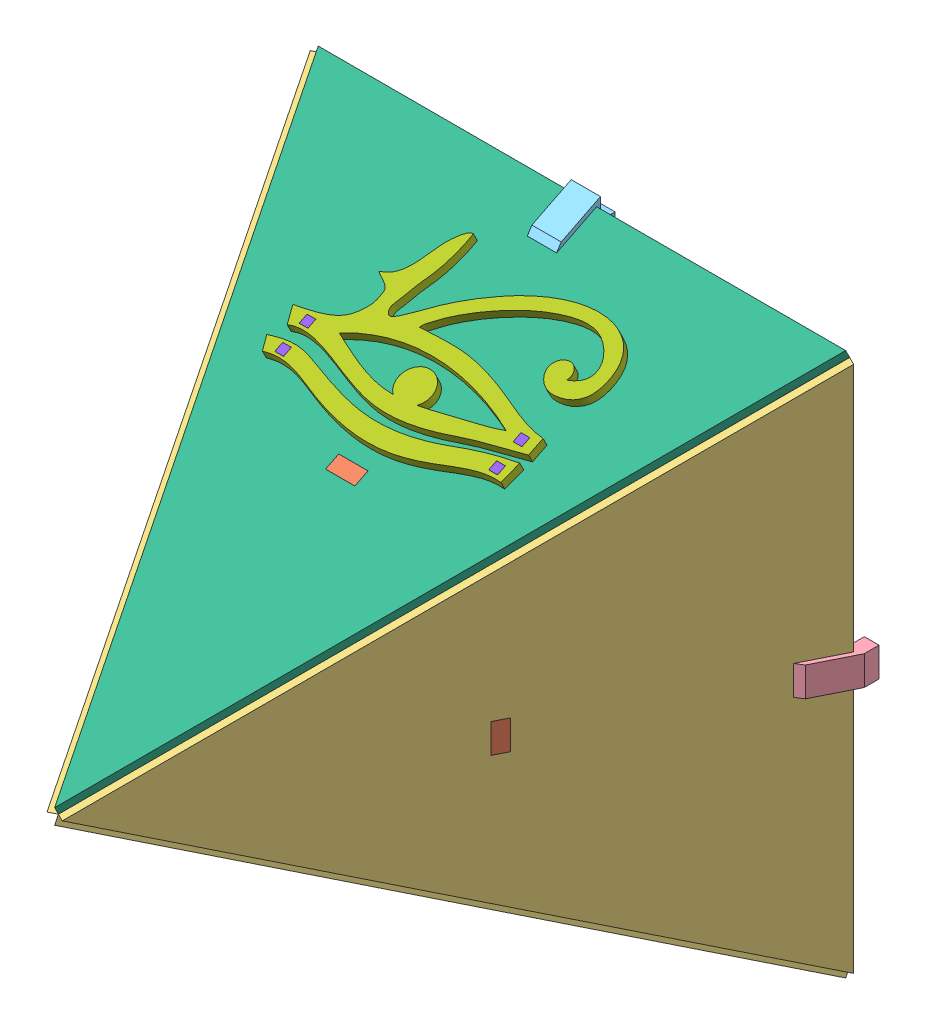
SolidWorks assembly asm_suport_ochi, configuration Default. Lengths in mm.
Overall size (194.12 191.31 188.41).
18 component instances, 8 part files, 52 mates.
Components (placement in the parent):
- suport_ochi-1: suport_ochi [Default] at (-11.0868 -7.0661 9.1509) size (100 100 3)
- carlig3_ochi-1: carlig3_ochi [Default] at (-16.0868 42.9197 12.1509) x (0 1 0) z (1 0 0) size (18.42 9.34 10)
- carlig3_ochi-2: carlig3_ochi [Default] at (38.899 -2.0661 12.1509) x (1 0 0) z (0 -1 0) size (18.42 9.34 10)
- carlig3_ochi-3: carlig3_ochi [Default] at (-61.0726 -12.0661 12.1509) x (-1 0 0) z (0 1 0) size (18.42 9.34 10)
- carlig3_ochi-4: carlig3_ochi [Default] at (-6.0868 -57.0519 12.1509) x (0 -1 0) z (-1 0 0) size (18.42 9.34 10)
- fata_ochi-1: fata_ochi [Default] at (-103.8033 -97.0661 -66.4803) x (0 1 0) z (0.894154 0 -0.447759) size (180 201.25 3)
- fata_ochi-2: fata_ochi [Default] at (-101.0868 -97.1001 -67.8236) x (1 0 0) z (0 -0.894154 0.447759) size (180 201.25 3)
- fata_ochi-4: fata_ochi [Default] at (78.9473 -97.0661 -67.8236) x (0 1 0) z (0.894154 0 0.447759) size (180 201.25 3)
- carlig1_ochi-1: carlig1_ochi [Default] at (-106.1203 -2.0661 -67.8116) x (-0.447759 0 -0.894154) z (0 -1 0) size (21.96 7 10)
- carlig1_ochi-2: carlig1_ochi [Default] at (83.9467 -12.0661 -67.8116) x (0.447759 0 -0.894154) z (0 1 0) size (21.96 7 10)
- carlig2_ochi-1: carlig2_ochi [Default] at (-6.0868 83.7223 -67.8209) x (0 0.447759 -0.894154) z (-1 0 0) size (18.83 13.03 10)
- carlig2_ochi-2: carlig2_ochi [Default] at (-16.0868 -97.8544 -67.8209) x (0 -0.447759 -0.894154) z (1 0 0) size (18.83 13.03 10)
- fata_ochi_frontal-1: fata_ochi_frontal [Default] at (78.9132 82.968 -67.8236) x (-1 0 0) z (0 0.894154 0.447759) size (180 201.25 3)
- ochi_ra-1: ochi_ra [Default] at (-11.0868 62.2627 -19.776) x (-1 0 0) z (0 0.894154 0.447759) size (87.5 62.9 3)
- suport_ochi_ra-1: suport_ochi_ra [Default] at (26.4255 57.1457 -2.8575) x (0 -0.894154 -0.447759) z (-1 0 0) size (4 3 3)
- suport_ochi_ra-2: suport_ochi_ra [Default] at (26.4255 57.7332 -12.9642) x (0 0.894154 0.447759) z (0 -0.447759 0.894154) size (4 3 3)
- suport_ochi_ra-3: suport_ochi_ra [Default] at (-48.5968 53.0695 -3.651) x (0 0.894154 0.447759) z (1 0 0) size (4 3 3)
- suport_ochi_ra-4: suport_ochi_ra [Default] at (-48.5968 57.2337 -11.9667) x (0 0.894154 0.447759) z (1 0 0) size (4 3 3)
Mates (geometry in assembly coordinates):
- Coincident1: coincident anti-aligned: plane of suport_ochi-1 through (-11.0868 -7.0661 9.1509) normal (0 0 -1); plane of carlig3_ochi-2 through (32.1532 -12.0661 9.1509) normal (0 0 1)
- Coincident2: coincident anti-aligned: plane of suport_ochi-1 through (-11.0868 -2.0661 12.1509) normal (0 -1 0); plane of carlig3_ochi-2 through (38.899 -2.0661 12.1509) normal (0 1 0)
- Coincident4: coincident anti-aligned: plane of suport_ochi-1 through (32.1532 -7.0661 12.1509) normal (1 0 0); plane of carlig3_ochi-2 through (32.1532 -12.0661 12.1509) normal (-1 0 0)
- Coincident5: coincident anti-aligned: plane of suport_ochi-1 through (-11.0868 -7.0661 9.1509) normal (0 0 -1); plane of carlig3_ochi-1 through (-6.0868 36.1739 9.1509) normal (0 0 1)
- Coincident6: coincident anti-aligned: plane of suport_ochi-1 through (-6.0868 -7.0661 12.1509) normal (-1 0 0); plane of carlig3_ochi-1 through (-6.0868 42.9197 12.1509) normal (1 0 0)
- Coincident7: coincident anti-aligned: plane of suport_ochi-1 through (-11.0868 36.1739 12.1509) normal (0 1 0); plane of carlig3_ochi-1 through (-6.0868 36.1739 12.1509) normal (0 -1 0)
- Coincident8: coincident anti-aligned: plane of suport_ochi-1 through (-11.0868 -7.0661 9.1509) normal (0 0 -1); plane of carlig3_ochi-3 through (-54.3268 -2.0661 9.1509) normal (0 0 1)
- Coincident9: coincident anti-aligned: plane of suport_ochi-1 through (-11.0868 -2.0661 12.1509) normal (0 -1 0); plane of carlig3_ochi-3 through (-61.0726 -2.0661 12.1509) normal (0 1 0)
- Coincident10: coincident anti-aligned: plane of suport_ochi-1 through (-54.3268 -7.0661 12.1509) normal (-1 0 0); plane of carlig3_ochi-3 through (-54.3268 -2.0661 12.1509) normal (1 0 0)
- Coincident11: coincident anti-aligned: plane of suport_ochi-1 through (-11.0868 -7.0661 12.1509) normal (0 0 1); plane of carlig3_ochi-4 through (-16.0868 -42.3061 12.1509) normal (0 0 -1)
- Coincident12: coincident anti-aligned: plane of suport_ochi-1 through (-16.0868 -7.0661 12.1509) normal (1 0 0); plane of carlig3_ochi-4 through (-16.0868 -57.0519 12.1509) normal (-1 0 0)
- Coincident13: coincident anti-aligned: plane of suport_ochi-1 through (-11.0868 -50.3061 12.1509) normal (0 -1 0); plane of carlig3_ochi-4 through (-16.0868 -50.3061 12.1509) normal (0 1 0)
- Coincident19: coincident aligned: plane of carlig3_ochi-4 through (-16.0868 -58.4824 15.9942) normal (0 -0.894154 0.447759); plane of fata_ochi-2 through (-101.0868 -99.7826 -66.4803) normal (0 -0.894154 0.447759)
- Coincident20: coincident anti-aligned: plane of carlig3_ochi-4 through (-16.0868 -60.7212 11.5234) normal (0 -0.447759 -0.894154); plane of fata_ochi-2 through (-101.0868 -60.7212 11.5234) normal (0 0.447759 0.894154)
- Coincident21: coincident anti-aligned: plane of carlig3_ochi-4 through (-16.0868 -57.0519 12.1509) normal (-1 0 0); plane of fata_ochi-2 through (-16.0868 -99.7826 -66.4803) normal (1 0 0)
- Coincident25: coincident anti-aligned: plane of carlig3_ochi-2 through (38.899 -2.0661 12.1509) normal (0 1 0); plane of fata_ochi-4 through (81.6297 -2.0661 -66.4803) normal (0 -1 0)
- Coincident26: coincident anti-aligned: plane of carlig3_ochi-2 through (42.5684 -12.0661 11.5234) normal (0.447759 0 -0.894154); plane of fata_ochi-4 through (42.5684 -97.0661 11.5234) normal (-0.447759 0 0.894154)
- Coincident27: coincident aligned: plane of carlig3_ochi-2 through (40.3296 -12.0661 15.9942) normal (0.894154 0 0.447759); plane of fata_ochi-4 through (81.6297 -97.0661 -66.4803) normal (0.894154 0 0.447759)
- Coincident28: coincident anti-aligned: plane of carlig3_ochi-3 through (-61.0726 -2.0661 12.1509) normal (0 1 0); plane of fata_ochi-1 through (-101.1208 -2.0661 -67.8236) normal (0 -1 0)
- Coincident29: coincident anti-aligned: plane of carlig3_ochi-3 through (-64.742 -2.0661 11.5234) normal (-0.447759 0 -0.894154); plane of fata_ochi-1 through (-62.0595 -97.0661 10.1802) normal (0.447759 0 0.894154)
- Coincident30: coincident aligned: plane of carlig3_ochi-3 through (-62.5032 -2.0661 15.9942) normal (-0.894154 0 0.447759); plane of fata_ochi-1 through (-103.8033 -97.0661 -66.4803) normal (-0.894154 0 0.447759)
- Coincident31: coincident anti-aligned: plane of fata_ochi-4 through (78.9473 -97.0661 -67.8236) normal (-0.894154 0 -0.447759); plane of carlig1_ochi-2 through (72.1145 -2.0661 -54.1788) normal (0.894154 0 0.447759)
- Coincident33: coincident anti-aligned: plane of fata_ochi-4 through (81.6297 -2.0661 -66.4803) normal (0 -1 0); plane of carlig1_ochi-2 through (83.9467 -2.0661 -67.8116) normal (0 1 0)
- Coincident34: coincident anti-aligned: plane of fata_ochi-4 through (81.6297 -97.0661 -66.4803) normal (0.894154 0 0.447759); plane of carlig1_ochi-2 through (78.379 -2.0661 -59.9887) normal (-0.894154 0 -0.447759)
- Coincident35: coincident anti-aligned: plane of fata_ochi-4 through (78.379 -97.0661 -59.9887) normal (0.447759 0 -0.894154); plane of carlig1_ochi-2 through (75.6965 -2.0661 -61.332) normal (-0.447759 0 0.894154)
- Coincident36: coincident anti-aligned: plane of fata_ochi-1 through (-103.8033 -97.0661 -66.4803) normal (-0.894154 0 0.447759); plane of carlig1_ochi-1 through (-100.5526 -12.0661 -59.9887) normal (0.894154 0 -0.447759)
- Coincident37: coincident anti-aligned: plane of fata_ochi-1 through (-101.1208 -12.0661 -67.8236) normal (0 1 0); plane of carlig1_ochi-1 through (-106.1203 -12.0661 -67.8116) normal (0 -1 0)
- Coincident38: coincident anti-aligned: plane of fata_ochi-1 through (-97.8701 -97.0661 -61.332) normal (-0.447759 0 -0.894154); plane of carlig1_ochi-1 through (-97.8701 -12.0661 -61.332) normal (0.447759 0 0.894154)
- Coincident42: coincident anti-aligned: plane of fata_ochi-2 through (-101.0868 -99.7826 -66.4803) normal (0 -0.894154 0.447759); plane of carlig2_ochi-2 through (-6.0868 -96.5319 -59.9887) normal (0 0.894154 -0.447759)
- Coincident43: coincident anti-aligned: plane of fata_ochi-2 through (-16.0868 -99.7826 -66.4803) normal (1 0 0); plane of carlig2_ochi-2 through (-16.0868 -97.8544 -67.8209) normal (-1 0 0)
- Coincident44: coincident anti-aligned: plane of fata_ochi-2 through (-101.0868 -96.5319 -59.9887) normal (0 -0.447759 -0.894154); plane of carlig2_ochi-2 through (-6.0868 -93.8494 -61.332) normal (0 0.447759 0.894154)
- Coincident51: coincident anti-aligned: plane of ochi_ra-1 through (23.4255 64.9452 -18.4328) normal (1 0 0); plane of suport_ochi_ra-1 through (23.4255 57.1457 -2.8575) normal (-1 0 0)
- Coincident52: coincident anti-aligned: plane of ochi_ra-1 through (-11.0868 55.8024 -0.1751) normal (0 0.447759 -0.894154); plane of suport_ochi_ra-1 through (23.4255 55.8024 -0.1751) normal (0 -0.447759 0.894154)
- Coincident53: coincident aligned: plane of ochi_ra-1 through (-11.0868 64.9452 -18.4328) normal (0 0.894154 0.447759); plane of suport_ochi_ra-1 through (23.4255 57.1457 -2.8575) normal (0 0.894154 0.447759)
- Coincident54: coincident anti-aligned: plane of ochi_ra-1 through (-45.5968 64.9452 -18.4328) normal (-1 0 0); plane of suport_ochi_ra-4 through (-45.5968 57.2337 -11.9667) normal (1 0 0)
- Coincident55: coincident anti-aligned: plane of ochi_ra-1 through (-11.0868 59.467 -7.4932) normal (0 0.447759 -0.894154); plane of suport_ochi_ra-4 through (-45.5968 55.8904 -9.2842) normal (0 -0.447759 0.894154)
- Coincident56: coincident aligned: plane of ochi_ra-1 through (-11.0868 64.9452 -18.4328) normal (0 0.894154 0.447759); plane of suport_ochi_ra-4 through (-45.5968 60.8103 -10.1756) normal (0 0.894154 0.447759)
- Coincident57: coincident anti-aligned: plane of ochi_ra-1 through (-45.5968 64.9452 -18.4328) normal (-1 0 0); plane of suport_ochi_ra-3 through (-45.5968 53.0695 -3.651) normal (1 0 0)
- Coincident58: coincident anti-aligned: plane of ochi_ra-1 through (-11.0868 55.3029 0.8225) normal (0 0.447759 -0.894154); plane of suport_ochi_ra-3 through (-45.5968 51.7262 -0.9686) normal (0 -0.447759 0.894154)
- Coincident59: coincident aligned: plane of ochi_ra-1 through (-11.0868 64.9452 -18.4328) normal (0 0.894154 0.447759); plane of suport_ochi_ra-3 through (-45.5968 56.6461 -1.86) normal (0 0.894154 0.447759)
- Coincident66: coincident anti-aligned: plane of ochi_ra-1 through (23.4255 64.9452 -18.4328) normal (1 0 0); plane of suport_ochi_ra-2 through (23.4255 56.3899 -10.2817) normal (-1 0 0)
- Coincident67: coincident anti-aligned: plane of ochi_ra-1 through (-11.0868 61.3098 -11.1732) normal (0 -0.447759 0.894154); plane of suport_ochi_ra-2 through (26.4255 57.7332 -12.9642) normal (0 0.447759 -0.894154)
- Coincident68: coincident aligned: plane of ochi_ra-1 through (-11.0868 64.9452 -18.4328) normal (0 0.894154 0.447759); plane of suport_ochi_ra-2 through (26.4255 59.9666 -8.4907) normal (0 0.894154 0.447759)
- Coincident75: coincident anti-aligned: plane of carlig2_ochi-1 through (-16.0868 82.3997 -59.9887) normal (0 -0.894154 -0.447759); plane of fata_ochi_frontal-1 through (78.9132 85.6504 -66.4803) normal (0 0.894154 0.447759)
- Coincident76: coincident anti-aligned: plane of carlig2_ochi-1 through (-6.0868 83.7223 -67.8209) normal (1 0 0); plane of fata_ochi_frontal-1 through (-6.0868 85.6504 -66.4803) normal (-1 0 0)
- Coincident77: coincident anti-aligned: plane of carlig2_ochi-1 through (-16.0868 79.7173 -61.332) normal (0 -0.447759 0.894154); plane of fata_ochi_frontal-1 through (78.9132 82.3997 -59.9887) normal (0 0.447759 -0.894154)
- Coincident78: coincident anti-aligned: plane of carlig3_ochi-1 through (-16.0868 42.9197 12.1509) normal (-1 0 0); plane of fata_ochi_frontal-1 through (-16.0868 85.6504 -66.4803) normal (1 0 0)
- Coincident79: coincident anti-aligned: plane of carlig3_ochi-1 through (-6.0868 41.6678 14.6509) normal (0 -0.447759 0.894154); plane of fata_ochi_frontal-1 through (78.9132 44.3503 15.9942) normal (0 0.447759 -0.894154)
- Coincident80: coincident aligned: plane of carlig3_ochi-1 through (-6.0868 44.3503 15.9942) normal (0 0.894154 0.447759); plane of fata_ochi_frontal-1 through (78.9132 85.6504 -66.4803) normal (0 0.894154 0.447759)
- Coincident81: coincident anti-aligned: plane of fata_ochi_frontal-1 through (-45.5968 85.6504 -66.4803) normal (-1 0 0); plane of suport_ochi_ra-3 through (-45.5968 53.0695 -3.651) normal (1 0 0)
- Coincident82: coincident anti-aligned: plane of fata_ochi_frontal-1 through (78.9132 53.9637 -3.2033) normal (0 -0.447759 0.894154); plane of suport_ochi_ra-3 through (-45.5968 53.0695 -3.651) normal (0 0.447759 -0.894154)
- Coincident83: coincident anti-aligned: plane of fata_ochi_frontal-1 through (78.9132 85.6504 -66.4803) normal (0 0.894154 0.447759); plane of ochi_ra-1 through (-11.0868 62.2627 -19.776) normal (0 -0.894154 -0.447759)
